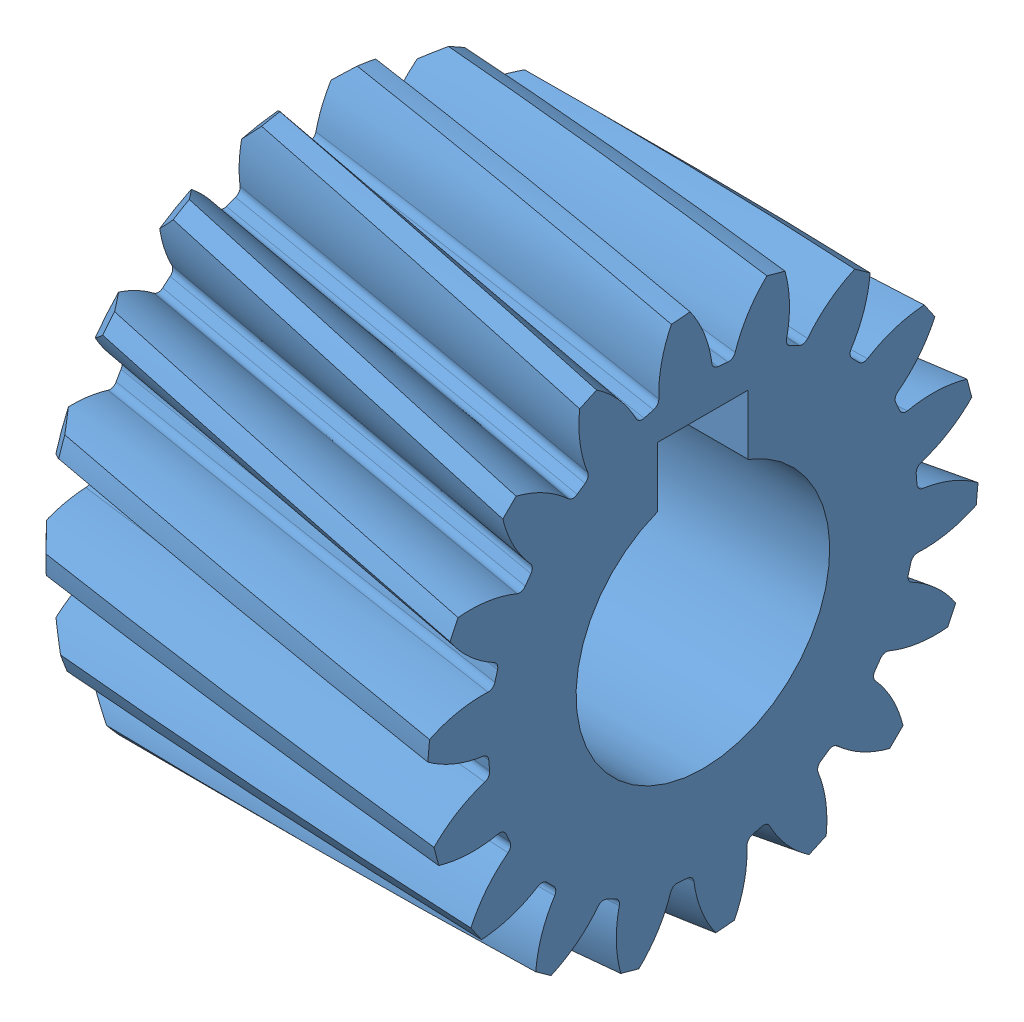
SolidWorks assembly first pinion, configuration Default. Lengths in mm.
Overall size (22 30.45 30.45).
2 component instances, 2 part files, 2 mates.
Components (placement in the parent):
- helical gear_3_am-3: helical gear_3_am [First Pinion] at (-22.0314 3.882 0) size (22 30.45 30.45)
- Part3^first pinion-1: Part3^first pinion [Default] at origin (virtual)
Mates (geometry in assembly coordinates):
- Coincident1: coincident: axis of helical gear_3_am-3 through (21.0417 -0.0314 3.882) axis (0 -1 0)
- Distance2: distance = 15.25 mm: line of assembly; line of assembly; axis of helical gear_3_am-3 through (21.0417 -0.0314 3.882) axis (0 -1 0)
